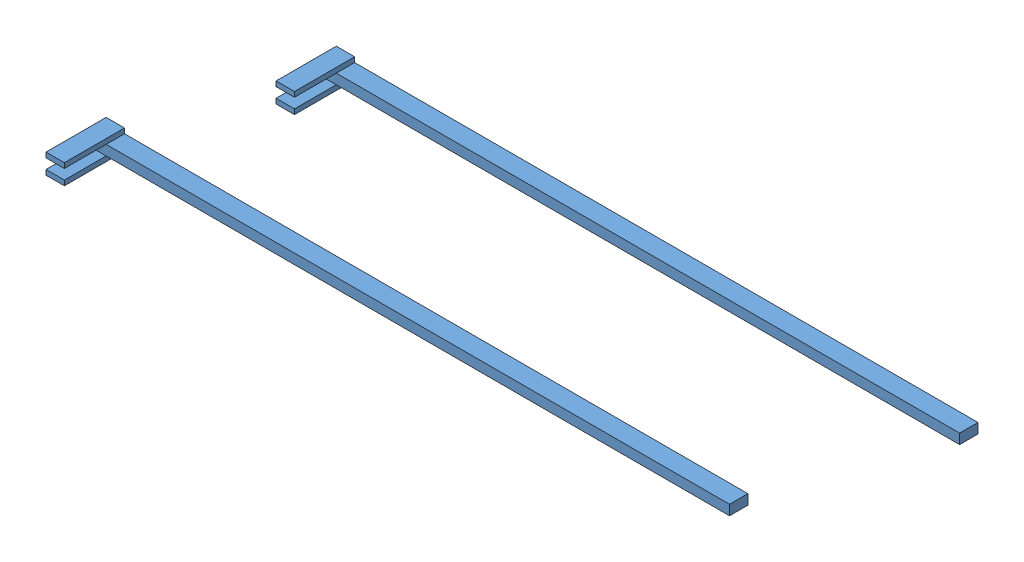
SolidWorks assembly Assem5, configuration Default. Lengths in mm.
Overall size (5794.06 663.82 1288.68).
2 component instances, 1 part files, 0 mates.
Components (placement in the parent):
- gallows top-1: gallows top [Default] at origin size (4876.8 152.4 457.2)
- gallows top-2: gallows top [Default] at (-917.2551 -511.4232 831.4764) size (4876.8 152.4 457.2)
